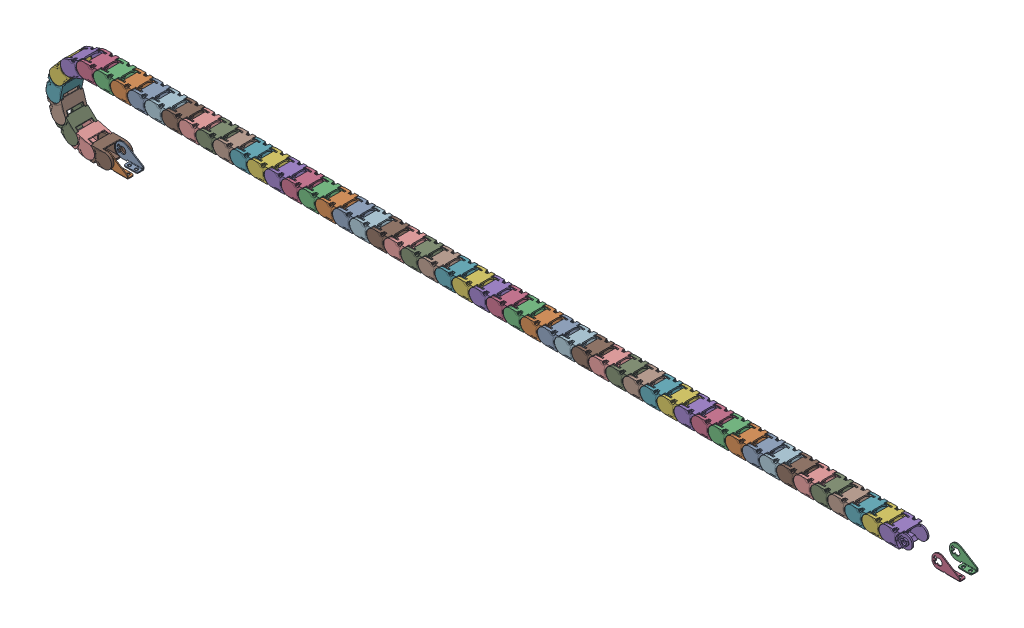
SolidWorks assembly MPSPS1520_50_57_S, configuration Default. Lengths in mm.
Overall size (1337.36 125.7 32).
59 component instances, 5 part files, 0 mates.
Components (placement in the parent):
- MPSPS1520_50_57_S_3-1: MPSPS1520_50_57_S_3 [Default] at (12.5 -10.5 -12.2) size (40.5 21 10)
- MPSPS1520_50_57_S_5-1: MPSPS1520_50_57_S_5 [Default] at (12.5 -10.5 12.2) size (40.5 21 10)
- MPSPS1520_50_57_S_7-1: MPSPS1520_50_57_S_7 [Default] at (1232.0376 89.5 -13.6) size (40.5 21 10)
- MPSPS1520_50_57_S_9-1: MPSPS1520_50_57_S_9 [Default] at (1232.0376 89.5 13.6) size (40.5 21 10)
- MPSPS1520_50_57_S_11-1: MPSPS1520_50_57_S_11 [Default] at (1169.5376 100 0) x (-1 0 0) z (0 0 1) size (45.05 21 32)
- MPSPS1520_50_57_S_11-2: MPSPS1520_50_57_S_11 [Default] at (1144.5376 100 0) x (-1 0 0) z (0 0 1) size (45.05 21 32)
- MPSPS1520_50_57_S_11-3: MPSPS1520_50_57_S_11 [Default] at (1119.5376 100 0) x (-1 0 0) z (0 0 1) size (45.05 21 32)
- MPSPS1520_50_57_S_11-4: MPSPS1520_50_57_S_11 [Default] at (1094.5376 100 0) x (-1 0 0) z (0 0 1) size (45.05 21 32)
- MPSPS1520_50_57_S_11-5: MPSPS1520_50_57_S_11 [Default] at (1069.5376 100 0) x (-1 0 0) z (0 0 1) size (45.05 21 32)
- MPSPS1520_50_57_S_11-6: MPSPS1520_50_57_S_11 [Default] at (1044.5376 100 0) x (-1 0 0) z (0 0 1) size (45.05 21 32)
- MPSPS1520_50_57_S_11-7: MPSPS1520_50_57_S_11 [Default] at (1019.5376 100 0) x (-1 0 0) z (0 0 1) size (45.05 21 32)
- MPSPS1520_50_57_S_11-8: MPSPS1520_50_57_S_11 [Default] at (994.5376 100 0) x (-1 0 0) z (0 0 1) size (45.05 21 32)
- MPSPS1520_50_57_S_11-9: MPSPS1520_50_57_S_11 [Default] at (969.5376 100 0) x (-1 0 0) z (0 0 1) size (45.05 21 32)
- MPSPS1520_50_57_S_11-10: MPSPS1520_50_57_S_11 [Default] at (944.5376 100 0) x (-1 0 0) z (0 0 1) size (45.05 21 32)
- MPSPS1520_50_57_S_11-11: MPSPS1520_50_57_S_11 [Default] at (919.5376 100 0) x (-1 0 0) z (0 0 1) size (45.05 21 32)
- MPSPS1520_50_57_S_11-12: MPSPS1520_50_57_S_11 [Default] at (894.5376 100 0) x (-1 0 0) z (0 0 1) size (45.05 21 32)
- MPSPS1520_50_57_S_11-13: MPSPS1520_50_57_S_11 [Default] at (869.5376 100 0) x (-1 0 0) z (0 0 1) size (45.05 21 32)
- MPSPS1520_50_57_S_11-14: MPSPS1520_50_57_S_11 [Default] at (844.5376 100 0) x (-1 0 0) z (0 0 1) size (45.05 21 32)
- MPSPS1520_50_57_S_11-15: MPSPS1520_50_57_S_11 [Default] at (819.5376 100 0) x (-1 0 0) z (0 0 1) size (45.05 21 32)
- MPSPS1520_50_57_S_11-16: MPSPS1520_50_57_S_11 [Default] at (794.5376 100 0) x (-1 0 0) z (0 0 1) size (45.05 21 32)
- MPSPS1520_50_57_S_11-17: MPSPS1520_50_57_S_11 [Default] at (769.5376 100 0) x (-1 0 0) z (0 0 1) size (45.05 21 32)
- MPSPS1520_50_57_S_11-18: MPSPS1520_50_57_S_11 [Default] at (744.5376 100 0) x (-1 0 0) z (0 0 1) size (45.05 21 32)
- MPSPS1520_50_57_S_11-19: MPSPS1520_50_57_S_11 [Default] at (719.5376 100 0) x (-1 0 0) z (0 0 1) size (45.05 21 32)
- MPSPS1520_50_57_S_11-20: MPSPS1520_50_57_S_11 [Default] at (694.5376 100 0) x (-1 0 0) z (0 0 1) size (45.05 21 32)
- MPSPS1520_50_57_S_11-21: MPSPS1520_50_57_S_11 [Default] at (669.5376 100 0) x (-1 0 0) z (0 0 1) size (45.05 21 32)
- MPSPS1520_50_57_S_11-22: MPSPS1520_50_57_S_11 [Default] at (644.5376 100 0) x (-1 0 0) z (0 0 1) size (45.05 21 32)
- MPSPS1520_50_57_S_11-23: MPSPS1520_50_57_S_11 [Default] at (619.5376 100 0) x (-1 0 0) z (0 0 1) size (45.05 21 32)
- MPSPS1520_50_57_S_11-24: MPSPS1520_50_57_S_11 [Default] at (594.5376 100 0) x (-1 0 0) z (0 0 1) size (45.05 21 32)
- MPSPS1520_50_57_S_11-25: MPSPS1520_50_57_S_11 [Default] at (569.5376 100 0) x (-1 0 0) z (0 0 1) size (45.05 21 32)
- MPSPS1520_50_57_S_11-26: MPSPS1520_50_57_S_11 [Default] at (544.5376 100 0) x (-1 0 0) z (0 0 1) size (45.05 21 32)
- MPSPS1520_50_57_S_11-27: MPSPS1520_50_57_S_11 [Default] at (519.5376 100 0) x (-1 0 0) z (0 0 1) size (45.05 21 32)
- MPSPS1520_50_57_S_11-28: MPSPS1520_50_57_S_11 [Default] at (494.5376 100 0) x (-1 0 0) z (0 0 1) size (45.05 21 32)
- MPSPS1520_50_57_S_11-29: MPSPS1520_50_57_S_11 [Default] at (469.5376 100 0) x (-1 0 0) z (0 0 1) size (45.05 21 32)
- MPSPS1520_50_57_S_11-30: MPSPS1520_50_57_S_11 [Default] at (444.5376 100 0) x (-1 0 0) z (0 0 1) size (45.05 21 32)
- MPSPS1520_50_57_S_11-31: MPSPS1520_50_57_S_11 [Default] at (419.5376 100 0) x (-1 0 0) z (0 0 1) size (45.05 21 32)
- MPSPS1520_50_57_S_11-32: MPSPS1520_50_57_S_11 [Default] at (394.5376 100 0) x (-1 0 0) z (0 0 1) size (45.05 21 32)
- MPSPS1520_50_57_S_11-33: MPSPS1520_50_57_S_11 [Default] at (369.5376 100 0) x (-1 0 0) z (0 0 1) size (45.05 21 32)
- MPSPS1520_50_57_S_11-34: MPSPS1520_50_57_S_11 [Default] at (344.5376 100 0) x (-1 0 0) z (0 0 1) size (45.05 21 32)
- MPSPS1520_50_57_S_11-35: MPSPS1520_50_57_S_11 [Default] at (319.5376 100 0) x (-1 0 0) z (0 0 1) size (45.05 21 32)
- MPSPS1520_50_57_S_11-36: MPSPS1520_50_57_S_11 [Default] at (294.5376 100 0) x (-1 0 0) z (0 0 1) size (45.05 21 32)
- MPSPS1520_50_57_S_11-37: MPSPS1520_50_57_S_11 [Default] at (269.5376 100 0) x (-1 0 0) z (0 0 1) size (45.05 21 32)
- MPSPS1520_50_57_S_11-38: MPSPS1520_50_57_S_11 [Default] at (244.5376 100 0) x (-1 0 0) z (0 0 1) size (45.05 21 32)
- MPSPS1520_50_57_S_11-39: MPSPS1520_50_57_S_11 [Default] at (219.5376 100 0) x (-1 0 0) z (0 0 1) size (45.05 21 32)
- MPSPS1520_50_57_S_11-40: MPSPS1520_50_57_S_11 [Default] at (194.5376 100 0) x (-1 0 0) z (0 0 1) size (45.05 21 32)
- MPSPS1520_50_57_S_11-41: MPSPS1520_50_57_S_11 [Default] at (169.5376 100 0) x (-1 0 0) z (0 0 1) size (45.05 21 32)
- MPSPS1520_50_57_S_11-42: MPSPS1520_50_57_S_11 [Default] at (144.5376 100 0) x (-1 0 0) z (0 0 1) size (45.05 21 32)
- MPSPS1520_50_57_S_11-43: MPSPS1520_50_57_S_11 [Default] at (119.5376 100 0) x (-1 0 0) z (0 0 1) size (45.05 21 32)
- MPSPS1520_50_57_S_11-44: MPSPS1520_50_57_S_11 [Default] at (94.5376 100 0) x (-1 0 0) z (0 0 1) size (45.05 21 32)
- MPSPS1520_50_57_S_11-45: MPSPS1520_50_57_S_11 [Default] at (69.5376 100 0) x (-1 0 0) z (0 0 1) size (45.05 21 32)
- MPSPS1520_50_57_S_11-46: MPSPS1520_50_57_S_11 [Default] at (44.5376 100 0) x (-1 0 0) z (0 0 1) size (45.05 21 32)
- MPSPS1520_50_57_S_11-47: MPSPS1520_50_57_S_11 [Default] at (19.5376 100 0) x (-1 0 0) z (0 0 1) size (45.05 21 32)
- MPSPS1520_50_57_S_11-48: MPSPS1520_50_57_S_11 [Default] at (-5.4615 99.8505 0) x (-0.999928 -0.011963 0) z (0 0 1) size (45.05 21 32)
- MPSPS1520_50_57_S_11-49: MPSPS1520_50_57_S_11 [Default] at (-29.65 95.2728 0) x (-0.935151 -0.354248 0) z (0 0 1) size (45.05 21 32)
- MPSPS1520_50_57_S_11-50: MPSPS1520_50_57_S_11 [Default] at (-49.4238 81.311 0) x (-0.646758 -0.762695 0) z (0 0 1) size (45.05 21 32)
- MPSPS1520_50_57_S_11-51: MPSPS1520_50_57_S_11 [Default] at (-59.9667 59.5215 0) x (-0.196675 -0.980469 0) z (0 0 1) size (45.05 21 32)
- MPSPS1520_50_57_S_11-52: MPSPS1520_50_57_S_11 [Default] at (-58.643 35.3516 0) x (0.302577 -0.953125 0) z (0 0 1) size (45.05 21 32)
- MPSPS1520_50_57_S_11-53: MPSPS1520_50_57_S_11 [Default] at (-45.7835 14.8438 0) x (0.726184 -0.6875 0) z (0 0 1) size (45.05 21 32)
- MPSPS1520_50_57_S_11-54: MPSPS1520_50_57_S_11 [Default] at (-24.6031 3.125 0) x (0.968246 -0.25 0) z (0 0 1) size (45.05 21 32)
- MPSPS1520_50_57_S_11-55: MPSPS1520_50_57_S_11 [Default] at origin size (45.05 21 32)
